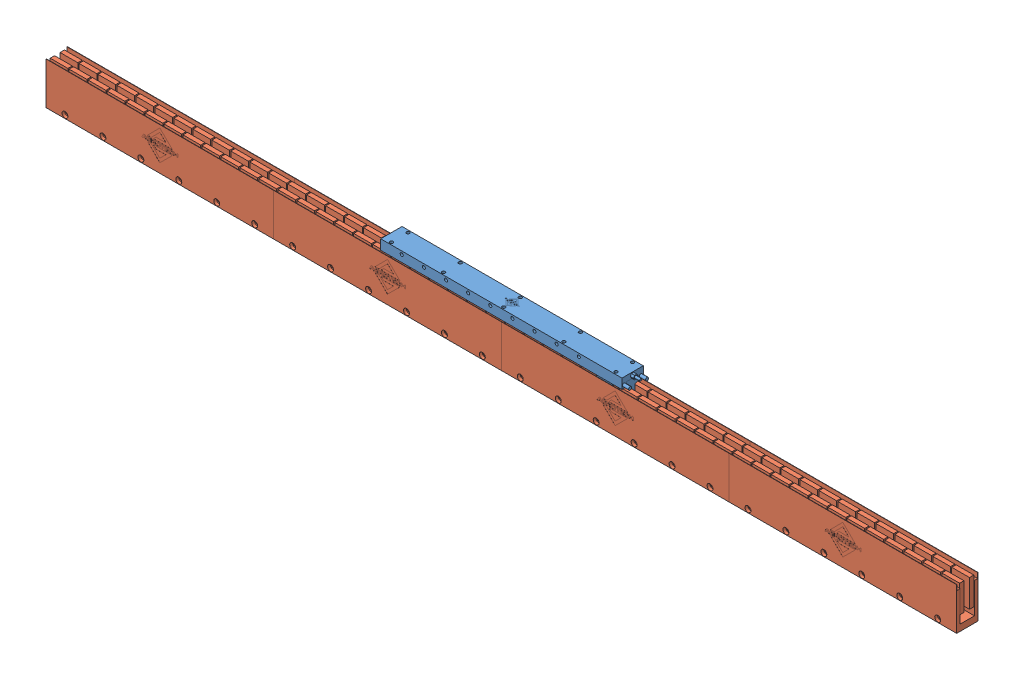
SolidWorks assembly AEROTECH-BLM-386_MT360P_MT360P_MT360P_MT360P, configuration BLM-386_MT360P_MT360P_MT360P_MT360P. Lengths in mm.
Overall size (1463.04 86.4 34.3).
5 component instances, 2 part files, 15 mates.
Components (placement in the parent):
- AEROTECH-BLM-386_MT360P_MT360P_MT360P_MT360P_BLM_FORCER-1: AEROTECH-BLM-386_MT360P_MT360P_MT360P_MT360P_BLM_FORCER [BLM-386] at origin size (400.6 74.68 34.3)
- AEROTECH-BLM-386_MT360P_MT360P_MT360P_MT360P_MT_TRACKS-1: AEROTECH-BLM-386_MT360P_MT360P_MT360P_MT360P_MT_TRACKS [MT360P] at (548.64 0 0) size (365.76 67.8 34.3)
- AEROTECH-BLM-386_MT360P_MT360P_MT360P_MT360P_MT_TRACKS-2: AEROTECH-BLM-386_MT360P_MT360P_MT360P_MT360P_MT_TRACKS [MT360P] at (182.88 0 0) size (365.76 67.8 34.3)
- AEROTECH-BLM-386_MT360P_MT360P_MT360P_MT360P_MT_TRACKS-3: AEROTECH-BLM-386_MT360P_MT360P_MT360P_MT360P_MT_TRACKS [MT360P] at (-182.88 0 0) size (365.76 67.8 34.3)
- AEROTECH-BLM-386_MT360P_MT360P_MT360P_MT360P_MT_TRACKS-4: AEROTECH-BLM-386_MT360P_MT360P_MT360P_MT360P_MT_TRACKS [MT360P] at (-548.64 0 0) size (365.76 67.8 34.3)
Mates (geometry in assembly coordinates):
- Coincident1: coincident aligned: plane of AEROTECH-BLM-386_MT360P_MT360P_MT360P_MT360P_MT_TRACKS-1 through (548.64 0 0) normal (0 0 1); plane of assembly through (0 0 0) normal (0 0 1)
- Coincident2: coincident aligned: plane of AEROTECH-BLM-386_MT360P_MT360P_MT360P_MT360P_MT_TRACKS-1 through (548.64 0 0) normal (0 1 0); plane of assembly through (0 0 0) normal (0 1 0)
- Coincident3: coincident anti-aligned: plane of AEROTECH-BLM-386_MT360P_MT360P_MT360P_MT360P_MT_TRACKS-1 through (365.76 -18.6 17.15) normal (-1 0 0); plane of AEROTECH-BLM-386_MT360P_MT360P_MT360P_MT360P_MT_TRACKS-2 through (365.76 -18.6 17.15) normal (1 0 0)
- Coincident4: coincident aligned: plane of AEROTECH-BLM-386_MT360P_MT360P_MT360P_MT360P_MT_TRACKS-2 through (182.88 0 0) normal (0 1 0); plane of assembly through (0 0 0) normal (0 1 0)
- Coincident5: coincident aligned: plane of AEROTECH-BLM-386_MT360P_MT360P_MT360P_MT360P_MT_TRACKS-2 through (182.88 0 0) normal (0 0 1); plane of assembly through (0 0 0) normal (0 0 1)
- Coincident6: coincident aligned: plane of AEROTECH-BLM-386_MT360P_MT360P_MT360P_MT360P_MT_TRACKS-1 through (548.64 0 0) normal (1 0 0); plane of assembly through (548.64 0 0) normal (1 0 0)
- Coincident7: coincident aligned: plane of AEROTECH-BLM-386_MT360P_MT360P_MT360P_MT360P_BLM_FORCER-1 through (0 0 0) normal (0 1 0); plane of assembly through (0 0 0) normal (0 1 0)
- Coincident8: coincident aligned: plane of AEROTECH-BLM-386_MT360P_MT360P_MT360P_MT360P_BLM_FORCER-1 through (0 0 0) normal (0 0 1); plane of assembly through (0 0 0) normal (0 0 1)
- Coincident9: coincident aligned: plane of AEROTECH-BLM-386_MT360P_MT360P_MT360P_MT360P_BLM_FORCER-1 through (0 0 0) normal (1 0 0); plane of assembly through (0 0 0) normal (1 0 0)
- Coincident10: coincident anti-aligned: plane of AEROTECH-BLM-386_MT360P_MT360P_MT360P_MT360P_MT_TRACKS-3 through (-365.76 -18.6 17.15) normal (-1 0 0); plane of AEROTECH-BLM-386_MT360P_MT360P_MT360P_MT360P_MT_TRACKS-4 through (-365.76 -18.6 17.15) normal (1 0 0)
- Coincident11: coincident anti-aligned: plane of AEROTECH-BLM-386_MT360P_MT360P_MT360P_MT360P_MT_TRACKS-2 through (0 -18.6 17.15) normal (-1 0 0); plane of AEROTECH-BLM-386_MT360P_MT360P_MT360P_MT360P_MT_TRACKS-3 through (0 -18.6 17.15) normal (1 0 0)
- Coincident12: coincident aligned: plane of AEROTECH-BLM-386_MT360P_MT360P_MT360P_MT360P_MT_TRACKS-3 through (-182.88 0 0) normal (0 0 1); plane of assembly through (0 0 0) normal (0 0 1)
- Coincident13: coincident aligned: plane of AEROTECH-BLM-386_MT360P_MT360P_MT360P_MT360P_MT_TRACKS-3 through (-182.88 0 0) normal (0 1 0); plane of assembly through (0 0 0) normal (0 1 0)
- Coincident14: coincident aligned: plane of AEROTECH-BLM-386_MT360P_MT360P_MT360P_MT360P_MT_TRACKS-4 through (-548.64 0 0) normal (0 0 1); plane of assembly through (0 0 0) normal (0 0 1)
- Coincident15: coincident aligned: plane of AEROTECH-BLM-386_MT360P_MT360P_MT360P_MT360P_MT_TRACKS-4 through (-548.64 0 0) normal (0 1 0); plane of assembly through (0 0 0) normal (0 1 0)
